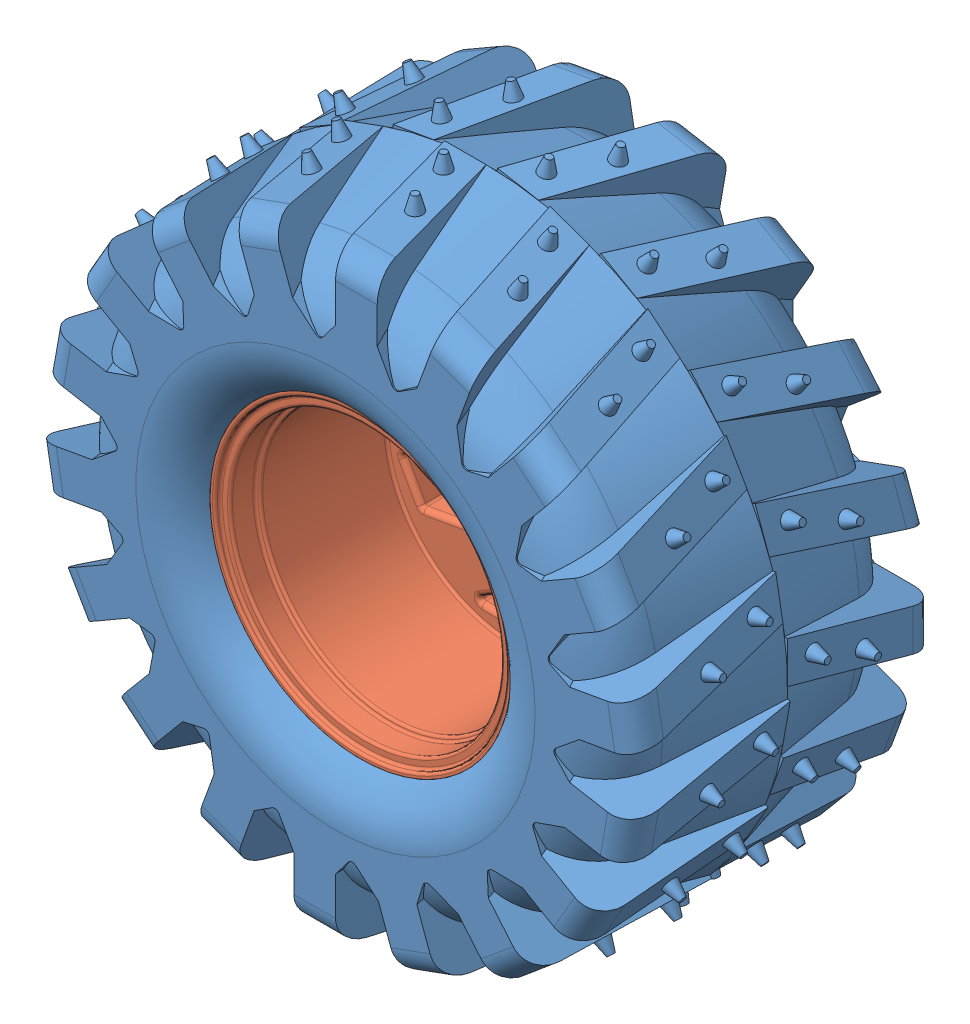
SolidWorks assembly Wheel, configuration Default. Lengths in mm.
Overall size (126 126 62.61).
2 component instances, 2 part files, 1 mates.
Components (placement in the parent):
- Tire-1: Tire [Varsayılan] at origin size (126 126 62.61)
- tire_rim-1: tire_rim [Varsayılan] at (-6.6946 4.5427 -50) size (60 60 50)
Mates (geometry in assembly coordinates):
- Coincident1: coincident aligned: circle of Tire-1; circle of tire_rim-1
